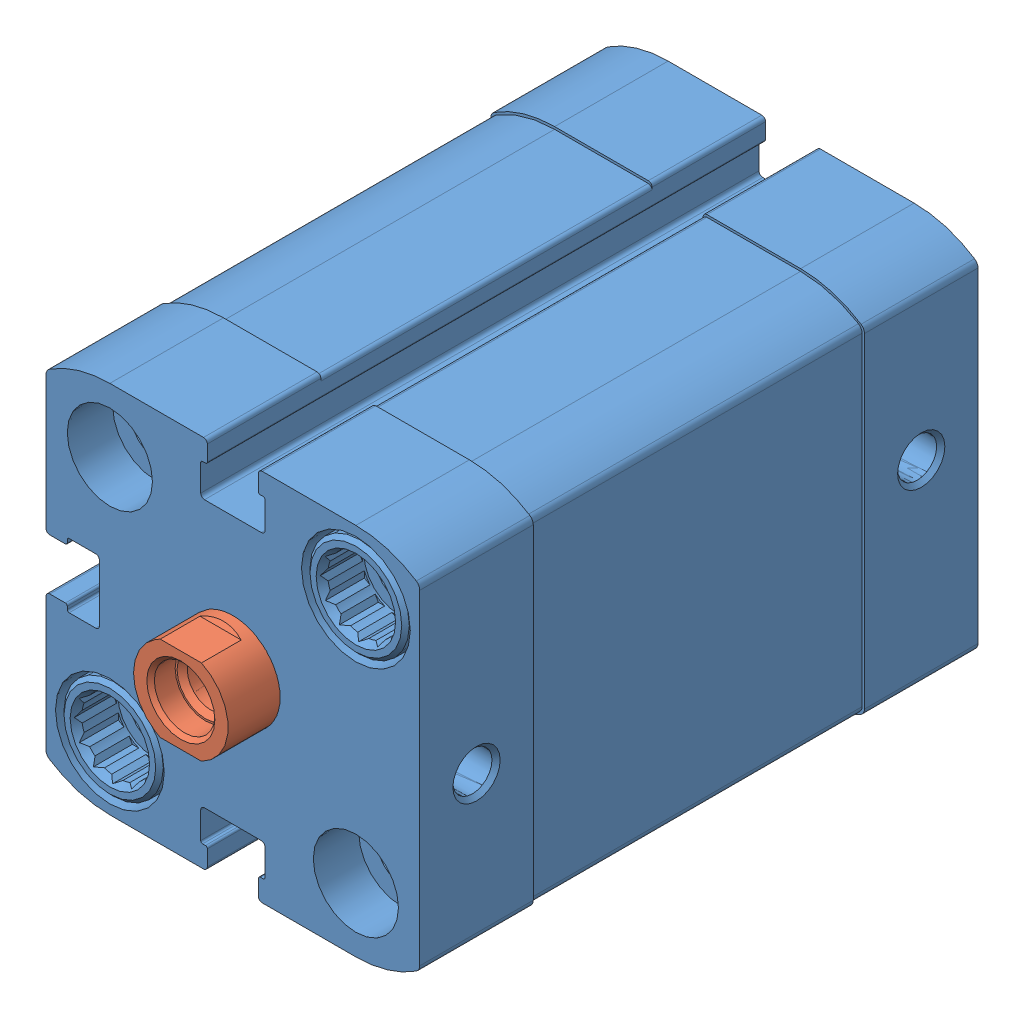
SolidWorks assembly Baugruppe172, configuration Standard. Lengths in mm.
Overall size (39.5 39.5 64.5).
2 component instances, 2 part files, 2 mates.
Components (placement in the parent):
- 536250_ADN_20_P____Z_-1: 536250_ADN_20_P____Z_ [Standard] at origin size (39.5 39.5 59)
- 536250_ADN_20_P_I__KS_-1: 536250_ADN_20_P_I__KS_ [Standard] x (0 0 -1) z (-1 0 0) size (52.5 25 25)
Mates (geometry in assembly coordinates):
- Deckungsgleich1: coincident anti-aligned: line of 536250_ADN_20_P____Z_-1 through (0 0 80.9) axis (0 0 -1); line of 536250_ADN_20_P_I__KS_-1 through (0 0 -80.9) axis (0 0 1)
- Winkel3: planar angle = 0 rad aligned: plane of 536250_ADN_20_P_I__KS_-1 through (0 0 0) normal (1 0 0); plane of 536250_ADN_20_P____Z_-1 through (0 0 0) normal (1 0 0)
